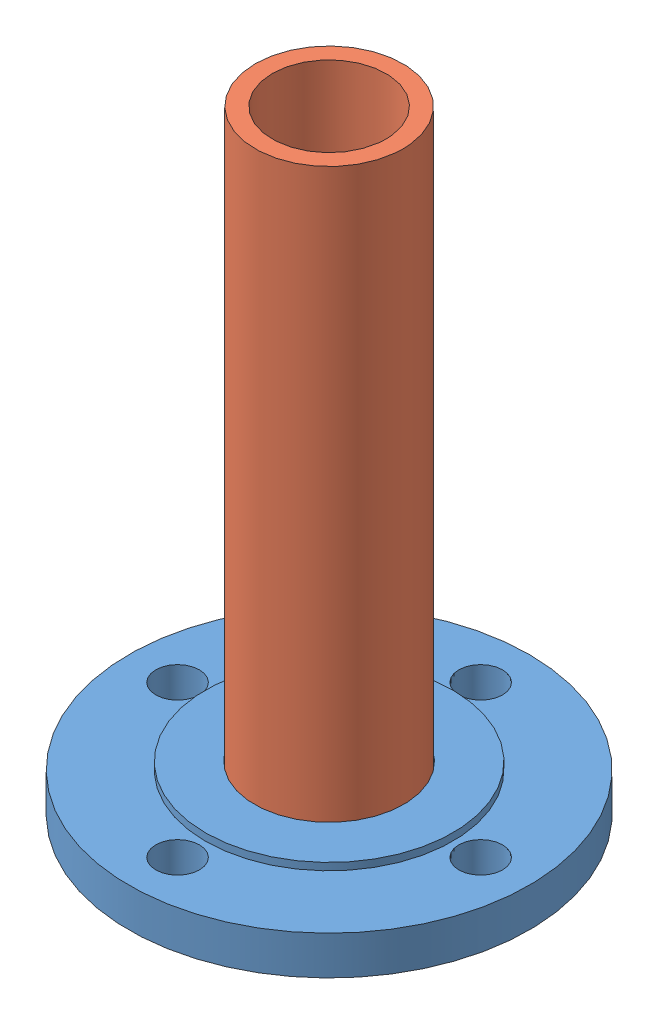
SolidWorks assembly Assem1, configuration Default. Lengths in mm.
Overall size (259.33 303.27 165).
2 component instances, 2 part files, 5 mates.
Components (placement in the parent):
- Bride plate DN 60.3-1: Bride plate DN 60.3 [Default] at origin size (259.33 123.26 165)
- DN 60.3 Epaisseur 8 mm-1: DN 60.3 Epaisseur 8 mm [Default] at (0 253 0) x (1 0 0) z (0 -1 0) size (60.9 60.9 250)
Mates (geometry in assembly coordinates):
- Coincident1: coincident aligned: plane of Bride plate DN 60.3-1 through (0 0 221.8936) normal (0 1 0)
- Coincident2: coincident aligned: plane of Bride plate DN 60.3-1 through (0 0 221.8936) normal (1 0 0)
- Coincident3: coincident aligned: plane of Bride plate DN 60.3-1 through (0 0 0) normal (0 0 1)
- Concentric1: concentric: cylinder of Bride plate DN 60.3-1 through (0 0 0) axis (0 -1 0) radius 82.5; cylinder of DN 60.3 Epaisseur 8 mm-1 through (0 20.8495 0) axis (0 1 0) radius 23.4515
- Distance1: distance = 3 mm aligned: plane of DN 60.3 Epaisseur 8 mm-1 through (0 3 0) normal (0 -1 0); plane of Bride plate DN 60.3-1 through (30.75 0 0) normal (0 -1 0)
